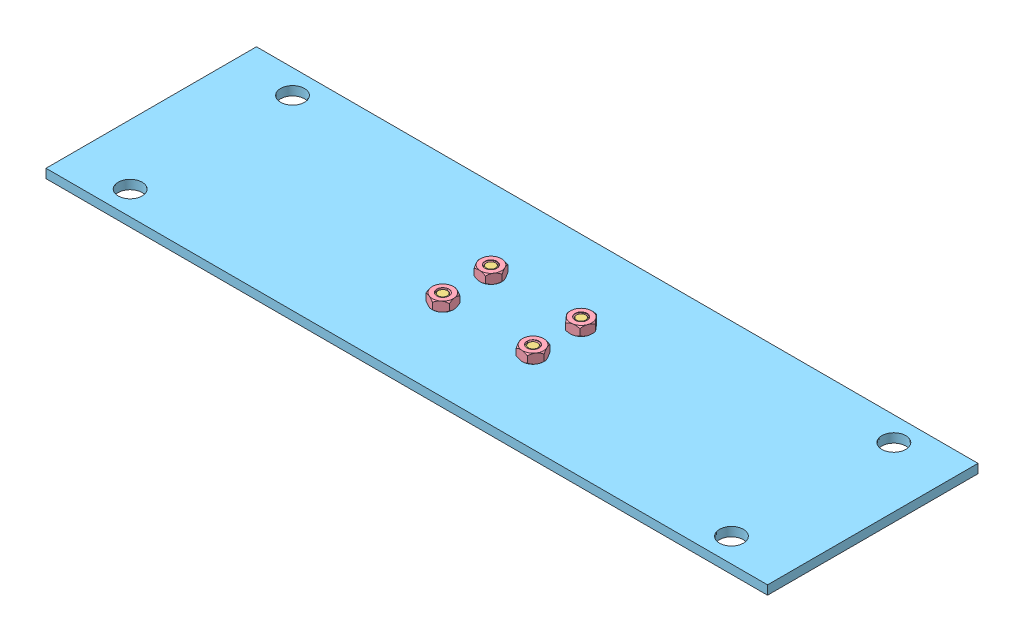
SolidWorks assembly Coupler_Assembly, configuration Default. Lengths in mm.
Overall size (240 22.2 70).
11 component instances, 5 part files, 23 mates.
Components (placement in the parent):
- Coupling_Holder-1: Coupling_Holder [Default] at origin size (40 12 25)
- M8_Coupling_Nut-1: M8_Coupling_Nut [M6] at (0 7 0) x (0 -0.5 0.866025) z (-1 0 0) size (10.52 12.06 18.71)
- M4_Screw-1: M4_Screw [По умолчанию] at (-15 0 8) x (0.351937 0 -0.936024) z (-0.936024 0 -0.351937) size (7 22 7)
- M4_Nut-1: M4_Nut [Default] at (-15 15 8) x (0.148284 0 0.988945) z (-0.988945 0 0.148284) size (8.89 3.2 7.81)
- M4_Screw-2: M4_Screw [По умолчанию] at (-15 0 -8) x (0.578044 0 -0.816006) z (-0.816006 0 -0.578044) size (7 22 7)
- M4_Screw-3: M4_Screw [По умолчанию] at (15 0 8) x (0.351937 0 -0.936024) z (-0.936024 0 -0.351937) size (7 22 7)
- M4_Screw-4: M4_Screw [По умолчанию] at (15 0 -8) x (0.351937 0 -0.936024) z (-0.936024 0 -0.351937) size (7 22 7)
- M4_Nut-2: M4_Nut [Default] at (-15 15 -8) x (0.549603 0 -0.835426) z (0.835426 0 0.549603) size (8.89 3.2 7.81)
- M4_Nut-3: M4_Nut [Default] at (15 15 -8) x (0.317801 0 -0.948157) z (0.948157 0 0.317801) size (8.89 3.2 7.81)
- M4_Nut-4: M4_Nut [Default] at (15 15 8) x (0.998121 0 0.06128) z (-0.06128 0 0.998121) size (8.89 3.2 7.81)
- CNC_SideARM_ConPlate-1: CNC_SideARM_ConPlate [Default] at (0 15 0) x (1 0 0) z (0 -1 0) size (240 70 3)
Mates (geometry in assembly coordinates):
- Coincident4: coordinate: point of Coupling_Holder-1
- Coincident8: coincident anti-aligned: plane of Coupling_Holder-1 through (9 2 2.8868) normal (0 1 0); plane of M8_Coupling_Nut-1 through (-9 2 -2.8868) normal (0 -1 0)
- Coincident9: coincident anti-aligned: plane of Coupling_Holder-1 through (9 7 5.7735) normal (0 0.5 -0.866025); plane of M8_Coupling_Nut-1 through (-9 2 2.8868) normal (0 -0.5 0.866025)
- Coincident10: coincident anti-aligned: plane of Coupling_Holder-1 through (-9 0 0) normal (1 0 0); plane of M8_Coupling_Nut-1 through (-9 7 0) normal (-1 0 0)
- Screw4: screw = 1 anti-aligned: cylinder of Coupling_Holder-1 through (-15 0 8) axis (0 1 0) radius 2; cylinder of M4_Screw-1 through (-15 18 8) axis (0 -1 0) radius 2
- LimitDistance1: limit distance = 0 mm anti-aligned: plane of M4_Screw-1 through (-15 0 8) normal (0 1 0); plane of Coupling_Holder-1 through (0 0 0) normal (0 -1 0)
- Concentric1: concentric anti-aligned: cylinder of Coupling_Holder-1 through (15 0 8) axis (0 1 0) radius 2; cylinder of M4_Screw-3 through (15 18 8) axis (0 -1 0) radius 2
- Concentric2: concentric aligned: cylinder of M4_Screw-3 through (15 18 8) axis (0 -1 0) radius 2; cylinder of M4_Nut-4 through (15 18.6917 8) axis (0 -1 0) radius 2
- Coincident12: coincident anti-aligned: plane of Coupling_Holder-1 through (0 0 0) normal (0 -1 0); plane of M4_Screw-3 through (15 0 8) normal (0 1 0)
- Concentric3: concentric anti-aligned: cylinder of Coupling_Holder-1 through (15 0 -8) axis (0 1 0) radius 2; cylinder of M4_Screw-4 through (15 18 -8) axis (0 -1 0) radius 2
- Concentric4: concentric aligned: cylinder of M4_Screw-4 through (15 18 -8) axis (0 -1 0) radius 2; cylinder of M4_Nut-3 through (15 18.2 -8) axis (0 -1 0) radius 2
- Coincident16: coincident anti-aligned: plane of Coupling_Holder-1 through (0 0 0) normal (0 -1 0); plane of M4_Screw-4 through (15 0 -8) normal (0 1 0)
- Concentric5: concentric anti-aligned: cylinder of Coupling_Holder-1 through (-15 0 -8) axis (0 1 0) radius 2; cylinder of M4_Screw-2 through (-15 18 -8) axis (0 -1 0) radius 2
- Concentric6: concentric aligned: cylinder of M4_Screw-2 through (-15 18 -8) axis (0 -1 0) radius 2; cylinder of M4_Nut-2 through (-15 18.2 -8) axis (0 -1 0) radius 2
- Coincident17: coincident anti-aligned: plane of Coupling_Holder-1 through (0 0 0) normal (0 -1 0); plane of M4_Screw-2 through (-15 0 -8) normal (0 1 0)
- Concentric7: concentric: cylinder of M4_Screw-1 through (-15 18 8) axis (0 -1 0) radius 2; cylinder of M4_Nut-1 through (-15 19.3086 8) axis (0 -1 0) radius 2
- Width1: width: plane of CNC_SideARM_ConPlate-1 through (-120 12 35) normal (0 0 1); plane of Coupling_Holder-1 through (-120 12 -35) normal (0 0 -1); plane of CNC_SideARM_ConPlate-1 through (20 12 -12.5) normal (0 0 -1); plane of Coupling_Holder-1 through (20 12 12.5) normal (0 0 1)
- Coincident18: coincident: plane of Coupling_Holder-1 through (0 12 0) normal (0 1 0); plane of CNC_SideARM_ConPlate-1 through (0 12 0) normal (0 -1 0)
- Width2: width anti-aligned: plane of CNC_SideARM_ConPlate-1 through (-120 12 -35) normal (-1 0 0); plane of Coupling_Holder-1 through (120 12 -35) normal (1 0 0); plane of CNC_SideARM_ConPlate-1 through (20 12 12.5) normal (1 0 0); plane of Coupling_Holder-1 through (-20 12 12.5) normal (-1 0 0)
- Coincident19: coincident anti-aligned: plane of M4_Nut-2 through (-15 15 -8) normal (0 -1 0); plane of CNC_SideARM_ConPlate-1 through (0 15 0) normal (0 1 0)
- Coincident20: coincident anti-aligned: plane of M4_Nut-3 through (15 15 -8) normal (0 -1 0); plane of CNC_SideARM_ConPlate-1 through (0 15 0) normal (0 1 0)
- Coincident21: coincident anti-aligned: plane of M4_Nut-4 through (15 15 8) normal (0 -1 0); plane of CNC_SideARM_ConPlate-1 through (0 15 0) normal (0 1 0)
- Coincident22: coincident anti-aligned: plane of M4_Nut-1 through (-15 15 8) normal (0 -1 0); plane of CNC_SideARM_ConPlate-1 through (0 15 0) normal (0 1 0)
